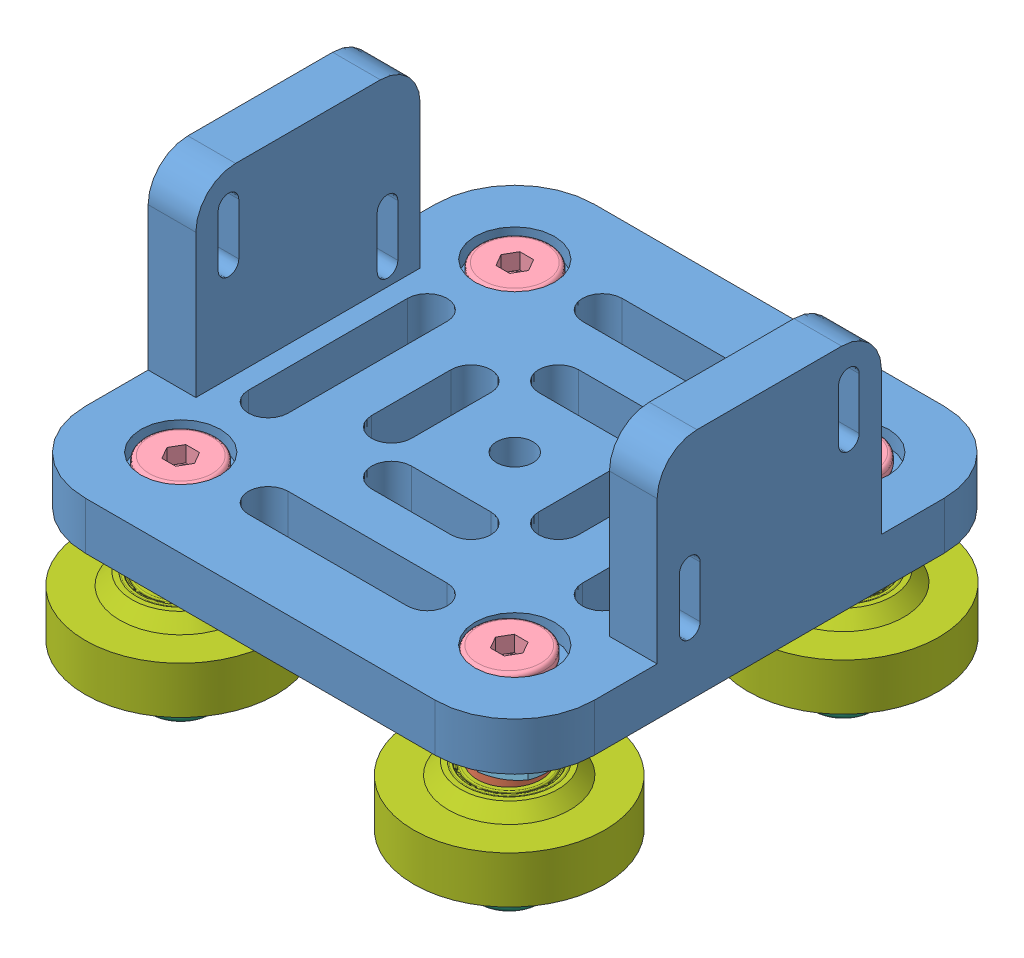
SolidWorks assembly MVG, configuration Default. Lengths in mm.
Overall size (65.3 50.32 66).
21 component instances, 7 part files, 59 mates.
Components (placement in the parent):
- MVG-P1-1: MVG-P1 [Default] at origin size (64 29 64)
- MVG-P2-1: MVG-P2 [Default] at (-21 -6.5 21) x (0 1 0) z (0 0 1) size (1 8 8)
- MVG-P2-2: MVG-P2 [Default] at (20.3 -6.5 21) x (0 1 0) z (0 0 -1) size (1 8 8)
- MVG-P2-4: MVG-P2 [Default] at (20.3 -6.5 -21) x (0 1 0) z (0 0 -1) size (1 8 8)
- MVG-P2-5: MVG-P2 [Default] at (-21 -6.5 -21) x (0 1 0) z (0 0 1) size (1 8 8)
- MVG-P3-1: MVG-P3 [Default] at (-21 -3 21) x (0 1 0) z (0 0 1) size (6 10 10)
- MVG-P3-2: MVG-P3 [Default] at (-21 -3 -21) x (0 1 0) z (0 0 1) size (6 10 10)
- MVG-P4-1: MVG-P4 [Default] at (-21 -7.675 21) x (0 1 0) z (0 0 1) size (26.97 8.9 8.9)
- MVG-P4-2: MVG-P4 [Default] at (-21 -7.675 -21) x (0 1 0) z (0 0 1) size (26.97 8.9 8.9)
- MVG-P4-3: MVG-P4 [Default] at (20.3 -7.675 21) x (0 1 0) z (0 0 1) size (26.97 8.9 8.9)
- MVG-P4-4: MVG-P4 [Default] at (20.3 -7.675 -21) x (0 1 0) z (0 0 1) size (26.97 8.9 8.9)
- MVG-P5-1: MVG-P5 [Default] at (21 -1.75 21) x (0 -1 0) z (0 0 -1) size (8.5 10 10)
- MVG-P5-2: MVG-P5 [Default] at (21 -1.75 -21) x (0 -1 0) z (0 0 -1) size (8.5 10 10)
- MVG-P6-1: MVG-P6 [Default] at (-21 -18.35 21) x (0 -1 0) z (0 0 -1) size (5 9.24 8)
- MVG-P6-7: MVG-P6 [Default] at (20.3 -18.35 21) x (0 -1 0) z (0 0 -1) size (5 9.24 8)
- MVG-P6-6: MVG-P6 [Default] at (20.3 -18.35 -21) x (0 -1 0) z (0 0 -1) size (5 9.24 8)
- MVG-P6-5: MVG-P6 [Default] at (-21 -18.35 -21) x (0 -1 0) z (0 0 1) size (5 9.24 8)
- MVG-P7-1: MVG-P7 [Default] at (-21 -11.45 21) x (0 0 -1) z (0 1 0) size (24 24 8.9)
- MVG-P7-2: MVG-P7 [Default] at (20.3 -11.45 21) x (0 0 1) z (0 1 0) size (24 24 8.9)
- MVG-P7-4: MVG-P7 [Default] at (20.3 -11.45 -21) x (0 0 1) z (0 1 0) size (24 24 8.9)
- MVG-P7-5: MVG-P7 [Default] at (-21 -11.45 -21) x (0 0 -1) z (0 1 0) size (24 24 8.9)
Mates (geometry in assembly coordinates):
- Концентричный1: concentric anti-aligned: cylinder of MVG-P3-1 through (-21 0 21) axis (0 -1 0) radius 2.55; cylinder of MVG-P1-1 through (-21 6 21) axis (0 1 0) radius 2.6
- Совпадение1: coincident anti-aligned: plane of MVG-P3-1 through (-21 0 21) normal (0 1 0); plane of MVG-P1-1 through (0 0 0) normal (0 -1 0)
- Параллельность1: parallel aligned: plane of MVG-P1-1 through (0 0 0) normal (0 0 1); plane of MVG-P3-1 through (-21 -3 21) normal (0 0 1)
- Концентричный2: concentric aligned: cylinder of MVG-P2-1 through (-21 -6 21) axis (0 -1 0) radius 2.6; cylinder of MVG-P3-1 through (-21 0 21) axis (0 -1 0) radius 2.55
- Совпадение2: coincident anti-aligned: plane of MVG-P2-1 through (-21 -6 21) normal (0 1 0); plane of MVG-P3-1 through (-21 -6 21) normal (0 -1 0)
- Совпадение3: coincident aligned: plane of MVG-P3-1 through (-21 -3 21) normal (0 0 1); plane of MVG-P2-1 through (-21 -6.5 21) normal (0 0 1)
- Концентричный3: concentric aligned: cylinder of MVG-P7-1 through (-21 -9 21) axis (0 -1 0) radius 2.5; cylinder of MVG-P2-1 through (-21 -6 21) axis (0 -1 0) radius 2.6
- Совпадение4: coincident anti-aligned: plane of MVG-P7-1 through (-21 -7 21) normal (0 1 0); plane of MVG-P2-1 through (-21 -7 21) normal (0 -1 0)
- Совпадение5: coincident anti-aligned: plane of MVG-P2-1 through (-21 -6.5 21) normal (0 0 1); plane of MVG-P7-1 through (-21 -11.45 21) normal (0 0 -1)
- Концентричный4: concentric aligned: cylinder of MVG-P4-1 through (-21 -7.675 21) axis (0 1 0) radius 2.5; cylinder of MVG-P1-1 through (-21 6 21) axis (0 1 0) radius 2.6
- Совпадение6: coincident anti-aligned: plane of MVG-P4-1 through (-24.95 4 21) normal (0 -1 0); plane of MVG-P1-1 through (-18.4 4 21) normal (0 1 0)
- Параллельность2: parallel aligned: plane of MVG-P1-1 through (0 0 0) normal (0 0 1); plane of MVG-P4-1 through (-21 -7.675 21) normal (0 0 1)
- Концентричный5: concentric aligned: cylinder of MVG-P6-1 through (-21 -15.9 21) axis (0 -1 0) radius 2.1; cylinder of MVG-P7-1 through (-21 -13.9 21) axis (0 -1 0) radius 2.5
- Совпадение7: coincident anti-aligned: plane of MVG-P6-1 through (-21 -15.9 13) normal (0 1 0); plane of MVG-P7-1 through (-21 -15.9 21) normal (0 -1 0)
- Совпадение8: coincident aligned: plane of MVG-P7-1 through (-21 -11.45 21) normal (0 0 -1); plane of MVG-P6-1 through (-21 -18.35 21) normal (0 0 -1)
- Параллельность3: parallel anti-aligned: plane of MVG-P1-1 through (0 0 0) normal (0 0 1); plane of MVG-P5-1 through (21 -1.75 21) normal (0 0 -1)
- Совпадение9: coincident anti-aligned: plane of MVG-P5-1 through (16 0 21) normal (0 1 0); plane of MVG-P1-1 through (0 0 0) normal (0 -1 0)
- Концентричный7: concentric aligned: cylinder of MVG-P2-2 through (20.3 -6 21) axis (0 -1 0) radius 2.6; cylinder of MVG-P7-2 through (20.3 -9 21) axis (0 -1 0) radius 2.5
- Совпадение10: coincident anti-aligned: plane of MVG-P2-2 through (20.3 -7 21) normal (0 -1 0); plane of MVG-P7-2 through (20.3 -7 21) normal (0 1 0)
- Совпадение11: coincident anti-aligned: plane of MVG-P2-2 through (20.3 -6.5 21) normal (0 0 -1); plane of MVG-P7-2 through (20.3 -11.45 21) normal (0 0 1)
- Концентричный8: concentric aligned: cylinder of MVG-P7-2 through (20.3 -13.9 21) axis (0 -1 0) radius 2.5; cylinder of MVG-P6-7 through (20.3 -15.9 21) axis (0 -1 0) radius 2.1
- Совпадение12: coincident anti-aligned: plane of MVG-P7-2 through (20.3 -15.9 21) normal (0 -1 0); plane of MVG-P6-7 through (20.3 -15.9 13) normal (0 1 0)
- Совпадение13: coincident anti-aligned: plane of MVG-P7-2 through (20.3 -11.45 21) normal (0 0 1); plane of MVG-P6-7 through (20.3 -18.35 21) normal (0 0 -1)
- Концентричный9: concentric aligned: cylinder of MVG-P2-2 through (20.3 -6 21) axis (0 -1 0) radius 2.6; cylinder of MVG-P5-1 through (20.3 2.5 21) axis (0 -1 0) radius 2.5
- Совпадение14: coincident anti-aligned: plane of MVG-P2-2 through (20.3 -6 21) normal (0 1 0); plane of MVG-P5-1 through (21 -6 21) normal (0 -1 0)
- Совпадение15: coincident aligned: plane of MVG-P5-1 through (21 -1.75 21) normal (0 0 -1); plane of MVG-P2-2 through (20.3 -6.5 21) normal (0 0 -1)
- Концентричный12: concentric aligned: cylinder of MVG-P2-5 through (-21 -6 -21) axis (0 -1 0) radius 2.6; cylinder of MVG-P3-2 through (-21 0 -21) axis (0 -1 0) radius 2.55
- Совпадение20: coincident anti-aligned: plane of MVG-P2-5 through (-21 -6 -21) normal (0 1 0); plane of MVG-P3-2 through (-21 -6 -21) normal (0 -1 0)
- Совпадение21: coincident aligned: plane of MVG-P3-2 through (-21 -3 -21) normal (0 0 1); plane of MVG-P2-5 through (-21 -6.5 -21) normal (0 0 1)
- Концентричный13: concentric aligned: cylinder of MVG-P7-5 through (-21 -9 -21) axis (0 -1 0) radius 2.5; cylinder of MVG-P2-5 through (-21 -6 -21) axis (0 -1 0) radius 2.6
- Совпадение22: coincident anti-aligned: plane of MVG-P7-5 through (-21 -7 -21) normal (0 1 0); plane of MVG-P2-5 through (-21 -7 -21) normal (0 -1 0)
- Совпадение23: coincident anti-aligned: plane of MVG-P7-5 through (-21 -11.45 -21) normal (0 0 -1); plane of MVG-P2-5 through (-21 -6.5 -21) normal (0 0 1)
- Концентричный14: concentric aligned: cylinder of MVG-P6-5 through (-21 -15.9 -21) axis (0 -1 0) radius 2.1; cylinder of MVG-P7-5 through (-21 -13.9 -21) axis (0 -1 0) radius 2.5
- Совпадение24: coincident anti-aligned: plane of MVG-P6-5 through (-21 -15.9 -13) normal (0 1 0); plane of MVG-P7-5 through (-21 -15.9 -21) normal (0 -1 0)
- Совпадение25: coincident anti-aligned: plane of MVG-P6-5 through (-21 -18.35 -21) normal (0 0 1); plane of MVG-P7-5 through (-21 -11.45 -21) normal (0 0 -1)
- Концентричный15: concentric aligned: cylinder of MVG-P7-4 through (20.3 -9 -21) axis (0 -1 0) radius 2.5; cylinder of MVG-P2-4 through (20.3 -6 -21) axis (0 -1 0) radius 2.6
- Совпадение26: coincident anti-aligned: plane of MVG-P7-4 through (20.3 -7 -21) normal (0 1 0); plane of MVG-P2-4 through (20.3 -7 -21) normal (0 -1 0)
- Совпадение27: coincident anti-aligned: plane of MVG-P7-4 through (20.3 -11.45 -21) normal (0 0 1); plane of MVG-P2-4 through (20.3 -6.5 -21) normal (0 0 -1)
- Концентричный16: concentric aligned: cylinder of MVG-P6-6 through (20.3 -15.9 -21) axis (0 -1 0) radius 2.1; cylinder of MVG-P7-4 through (20.3 -13.9 -21) axis (0 -1 0) radius 2.5
- Совпадение28: coincident anti-aligned: plane of MVG-P6-6 through (20.3 -15.9 -29) normal (0 1 0); plane of MVG-P7-4 through (20.3 -15.9 -21) normal (0 -1 0)
- Совпадение29: coincident anti-aligned: plane of MVG-P6-6 through (20.3 -18.35 -21) normal (0 0 -1); plane of MVG-P7-4 through (20.3 -11.45 -21) normal (0 0 1)
- Концентричный17: concentric aligned: cylinder of MVG-P2-4 through (20.3 -6 -21) axis (0 -1 0) radius 2.6; cylinder of MVG-P5-2 through (20.3 2.5 -21) axis (0 -1 0) radius 2.5
- Совпадение30: coincident anti-aligned: plane of MVG-P2-4 through (20.3 -6 -21) normal (0 1 0); plane of MVG-P5-2 through (21 -6 -21) normal (0 -1 0)
- Совпадение31: coincident aligned: plane of MVG-P2-4 through (20.3 -6.5 -21) normal (0 0 -1); plane of MVG-P5-2 through (21 -1.75 -21) normal (0 0 -1)
- Концентричный18: concentric: cylinder of MVG-P3-2 through (-21 0 -21) axis (0 -1 0) radius 2.55; cylinder of MVG-P1-1 through (-21 6 -21) axis (0 1 0) radius 2.6
- Совпадение32: coincident anti-aligned: plane of MVG-P3-2 through (-21 0 -21) normal (0 1 0); plane of MVG-P1-1 through (0 0 0) normal (0 -1 0)
- Параллельность4: parallel aligned: plane of MVG-P1-1 through (0 0 0) normal (0 0 1); plane of MVG-P3-2 through (-21 -3 -21) normal (0 0 1)
- Параллельность5: parallel anti-aligned: plane of MVG-P1-1 through (0 0 0) normal (0 0 1); plane of MVG-P5-2 through (21 -1.75 -21) normal (0 0 -1)
- Совпадение33: coincident anti-aligned: plane of MVG-P5-2 through (16 0 -21) normal (0 1 0); plane of MVG-P1-1 through (0 0 0) normal (0 -1 0)
- Концентричный20: concentric: cylinder of MVG-P4-2 through (-21 -7.675 -21) axis (0 1 0) radius 2.5; cylinder of MVG-P1-1 through (-21 6 -21) axis (0 1 0) radius 2.6
- Совпадение34: coincident: plane of MVG-P4-2 through (-24.95 4 -21) normal (0 -1 0); plane of MVG-P1-1 through (-18.4 4 -21) normal (0 1 0)
- Параллельность6: parallel aligned: plane of MVG-P1-1 through (0 0 0) normal (0 0 1); plane of MVG-P4-2 through (-21 -7.675 -21) normal (0 0 1)
- Концентричный21: concentric anti-aligned: cylinder of MVG-P4-3 through (20.3 -7.675 21) axis (0 1 0) radius 2.5; cylinder of MVG-P5-1 through (20.3 2.5 21) axis (0 -1 0) radius 2.5
- Совпадение35: coincident anti-aligned: plane of MVG-P4-3 through (16.35 4 21) normal (0 -1 0); plane of MVG-P5-1 through (21 4 21) normal (0 1 0)
- Совпадение36: coincident anti-aligned: plane of MVG-P5-1 through (21 -1.75 21) normal (0 0 -1); plane of MVG-P4-3 through (20.3 -7.675 21) normal (0 0 1)
- Концентричный22: concentric anti-aligned: cylinder of MVG-P4-4 through (20.3 -7.675 -21) axis (0 1 0) radius 2.5; cylinder of MVG-P5-2 through (20.3 2.5 -21) axis (0 -1 0) radius 2.5
- Совпадение37: coincident anti-aligned: plane of MVG-P4-4 through (16.35 4 -21) normal (0 -1 0); plane of MVG-P5-2 through (21 4 -21) normal (0 1 0)
- Совпадение38: coincident anti-aligned: plane of MVG-P5-2 through (21 -1.75 -21) normal (0 0 -1); plane of MVG-P4-4 through (20.3 -7.675 -21) normal (0 0 1)
- Concentric1: concentric: cylinder of MVG-P1-1 through (21 6 21) axis (0 1 0) radius 3.7; cylinder of MVG-P5-1 through (21 -1.75 21) axis (0 1 0) radius 3.55
